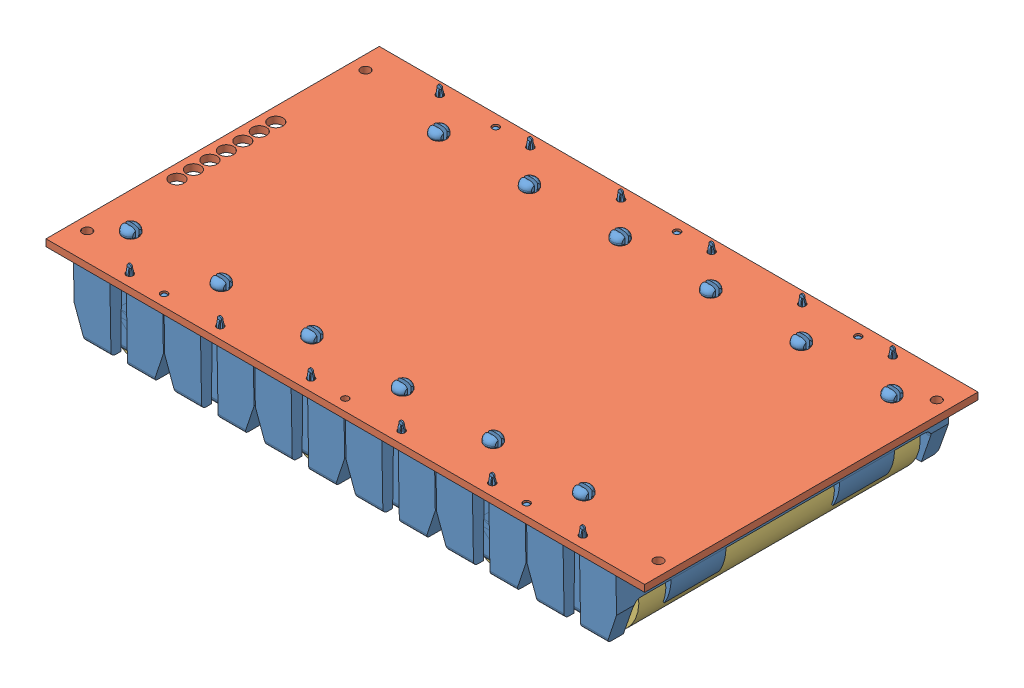
SolidWorks assembly PCB_Battery Assembly, configuration Default. Lengths in mm.
Overall size (138.43 24.87 77.22).
13 component instances, 3 part files, 30 mates.
Components (placement in the parent):
- Battery Holder - keystone-PN1043-1: Battery Holder - keystone-PN1043 [Default] at (-125.3925 103.3982 18.9155) x (1 0 0) z (0 0 -1) size (20.65 18.93 77.14)
- Battery PCB-1: Battery PCB [Default] at (-148.3186 115.135 -16.9005) x (1 0 0) z (0 -1 0) size (138.43 77.06 1.59)
- battery_6612-1: battery_6612 [Default] at (-117.0385 104.4035 -11.3639) x (-0.413992 0.91028 0) z (0.91028 0.413992 0) size (18.3 65.05 18.3)
- battery_6612-2: battery_6612 [Default] at (-137.9935 104.4035 54.6265) x (-0.916106 0.400937 0) z (-0.400937 -0.916106 0) size (18.3 65.05 18.3)
- Battery Holder - keystone-PN1043-2: Battery Holder - keystone-PN1043 [Default] at (-129.6396 103.3982 24.3471) x (-1 0 0) z (0 0 1) size (20.65 18.93 77.14)
- Battery Holder - keystone-PN1043-3: Battery Holder - keystone-PN1043 [Default] at (-104.4375 103.3982 18.9155) x (1 0 0) z (0 0 -1) size (20.65 18.93 77.14)
- battery_6612-3: battery_6612 [Default] at (-96.0835 104.4035 -10.3735) x (1 0 0) z (0 -1 0) size (18.3 65.05 18.3)
- Battery Holder - keystone-PN1043-4: Battery Holder - keystone-PN1043 [Default] at (-83.4825 103.3982 18.9155) x (1 0 0) z (0 0 -1) size (20.65 18.93 77.14)
- Battery Holder - keystone-PN1043-5: Battery Holder - keystone-PN1043 [Default] at (-45.8196 103.3982 24.3471) x (-1 0 0) z (0 0 1) size (20.65 18.93 77.14)
- Battery Holder - keystone-PN1043-6: Battery Holder - keystone-PN1043 [Default] at (-41.5725 103.3982 18.9155) x (1 0 0) z (0 0 -1) size (20.65 18.93 77.14)
- battery_6612-4: battery_6612 [Default] at (-75.1285 104.4035 -11.3639) x (-0.923728 -0.383049 0) z (-0.383049 0.923728 0) size (18.3 65.05 18.3)
- battery_6612-5: battery_6612 [Default] at (-54.1735 104.4035 54.6265) x (-1 0 0) z (0 -1 0) size (18.3 65.05 18.3)
- battery_6612-6: battery_6612 [Default] at (-33.2185 104.4035 -11.3639) x (-0.923728 -0.383049 0) z (-0.383049 0.923728 0) size (18.3 65.05 18.3)
Mates (geometry in assembly coordinates):
- Concentric1: concentric anti-aligned: cylinder of Battery Holder - keystone-PN1043-1 through (-117.0385 104.4035 -12.8111) axis (0 0 1) radius 9.144; cylinder of battery_6612-1 through (-117.0385 104.4035 53.6861) axis (0 0 -1) radius 9.15
- Coincident2: coincident anti-aligned: plane of Battery Holder - keystone-PN1043-1 through (-113.8635 103.7431 53.6861) normal (0 0 -1); plane of battery_6612-1 through (-117.0385 104.4035 53.6861) normal (0 0 1)
- Concentric4: concentric anti-aligned: cylinder of Battery Holder - keystone-PN1043-3 through (-96.0835 104.4035 -12.8111) axis (0 0 1) radius 9.144; cylinder of battery_6612-3 through (-96.0835 104.4035 54.6765) axis (0 0 -1) radius 9.15
- Coincident4: coincident anti-aligned: plane of Battery Holder - keystone-PN1043-3 through (-99.2585 103.7431 -10.3735) normal (0 0 1); plane of battery_6612-3 through (-96.0835 104.4035 -10.3735) normal (0 0 -1)
- Concentric5: concentric anti-aligned: cylinder of battery_6612-2 through (-137.9935 104.4035 -10.4235) axis (0 0 1) radius 9.15; cylinder of Battery Holder - keystone-PN1043-2 through (-137.9935 104.4035 56.0737) axis (0 0 -1) radius 9.144
- Coincident5: coincident anti-aligned: plane of battery_6612-2 through (-137.9935 104.4035 -10.4235) normal (0 0 -1); plane of Battery Holder - keystone-PN1043-2 through (-141.1685 103.7431 -10.4235) normal (0 0 1)
- Concentric12: concentric anti-aligned: cylinder of Battery PCB-1 through (-145.9945 113.5475 49.2538) axis (0 1 0) radius 1.7145; cylinder of Battery Holder - keystone-PN1043-2 through (-145.9945 113.5475 49.2538) axis (0 -1 0) radius 1.4605
- Coincident9: coincident aligned: plane of Battery PCB-1 through (-148.3186 113.5475 -16.9005) normal (0 -1 0); plane of Battery Holder - keystone-PN1043-2 through (-127.6684 113.5475 56.0737) normal (0 -1 0)
- Concentric13: concentric anti-aligned: cylinder of Battery PCB-1 through (-129.9925 113.5475 -5.9912) axis (0 1 0) radius 1.7145; cylinder of Battery Holder - keystone-PN1043-2 through (-129.9925 113.5475 -5.9912) axis (0 -1 0) radius 1.4605
- Coincident10: coincident aligned: plane of Battery Holder - keystone-PN1043-1 through (-127.3636 113.5475 -12.8111) normal (0 -1 0); plane of Battery PCB-1 through (-148.3186 113.5475 -16.9005) normal (0 -1 0)
- Concentric14: concentric anti-aligned: cylinder of Battery Holder - keystone-PN1043-1 through (-125.0395 113.5475 49.2538) axis (0 -1 0) radius 1.4605; cylinder of Battery PCB-1 through (-125.0395 113.5475 49.2538) axis (0 1 0) radius 1.7145
- Concentric15: concentric anti-aligned: cylinder of Battery Holder - keystone-PN1043-1 through (-109.0375 113.5475 -5.9912) axis (0 -1 0) radius 1.4605; cylinder of Battery PCB-1 through (-109.0375 113.5475 -5.9912) axis (0 1 0) radius 1.7145
- Coincident11: coincident aligned: plane of Battery PCB-1 through (-148.3186 113.5475 -16.9005) normal (0 -1 0); plane of Battery Holder - keystone-PN1043-3 through (-106.4086 113.5475 -12.8111) normal (0 -1 0)
- Concentric16: concentric anti-aligned: cylinder of Battery PCB-1 through (-104.0845 113.5475 49.2538) axis (0 1 0) radius 1.7145; cylinder of Battery Holder - keystone-PN1043-3 through (-104.0845 113.5475 49.2538) axis (0 -1 0) radius 1.4605
- Concentric17: concentric anti-aligned: cylinder of Battery PCB-1 through (-88.0825 113.5475 -5.9912) axis (0 1 0) radius 1.7145; cylinder of Battery Holder - keystone-PN1043-3 through (-88.0825 113.5475 -5.9912) axis (0 -1 0) radius 1.4605
- Concentric18: concentric anti-aligned: cylinder of Battery Holder - keystone-PN1043-6 through (-33.2185 104.4035 -12.8111) axis (0 0 1) radius 9.144; cylinder of battery_6612-6 through (-33.2185 104.4035 53.6861) axis (0 0 -1) radius 9.15
- Coincident12: coincident anti-aligned: plane of Battery Holder - keystone-PN1043-6 through (-30.0435 103.7431 53.6861) normal (0 0 -1); plane of battery_6612-6 through (-33.2185 104.4035 53.6861) normal (0 0 1)
- Concentric19: concentric anti-aligned: cylinder of Battery Holder - keystone-PN1043-5 through (-54.1735 104.4035 56.0737) axis (0 0 -1) radius 9.144; cylinder of battery_6612-5 through (-54.1735 104.4035 -10.4235) axis (0 0 1) radius 9.15
- Coincident13: coincident anti-aligned: plane of Battery Holder - keystone-PN1043-5 through (-57.3485 103.7431 -10.4235) normal (0 0 1); plane of battery_6612-5 through (-54.1735 104.4035 -10.4235) normal (0 0 -1)
- Concentric20: concentric anti-aligned: cylinder of Battery Holder - keystone-PN1043-4 through (-75.1285 104.4035 -12.8111) axis (0 0 1) radius 9.144; cylinder of battery_6612-4 through (-75.1285 104.4035 53.6861) axis (0 0 -1) radius 9.15
- Coincident14: coincident anti-aligned: plane of Battery Holder - keystone-PN1043-4 through (-71.9535 103.7431 53.6861) normal (0 0 -1); plane of battery_6612-4 through (-75.1285 104.4035 53.6861) normal (0 0 1)
- Coincident15: coincident aligned: plane of Battery PCB-1 through (-148.3186 113.5475 -16.9005) normal (0 -1 0); plane of Battery Holder - keystone-PN1043-4 through (-85.4536 113.5475 -12.8111) normal (0 -1 0)
- Concentric21: concentric anti-aligned: cylinder of Battery PCB-1 through (-83.1295 113.5475 49.2538) axis (0 1 0) radius 1.7145; cylinder of Battery Holder - keystone-PN1043-4 through (-83.1295 113.5475 49.2538) axis (0 -1 0) radius 1.4605
- Concentric22: concentric anti-aligned: cylinder of Battery PCB-1 through (-67.1275 113.5475 -5.9912) axis (0 1 0) radius 1.7145; cylinder of Battery Holder - keystone-PN1043-4 through (-67.1275 113.5475 -5.9912) axis (0 -1 0) radius 1.4605
- Coincident16: coincident aligned: plane of Battery PCB-1 through (-148.3186 113.5475 -16.9005) normal (0 -1 0); plane of Battery Holder - keystone-PN1043-5 through (-43.8484 113.5475 56.0737) normal (0 -1 0)
- Concentric23: concentric anti-aligned: cylinder of Battery Holder - keystone-PN1043-5 through (-62.1745 113.5475 49.2538) axis (0 -1 0) radius 1.4605; cylinder of Battery PCB-1 through (-62.1745 113.5475 49.2538) axis (0 1 0) radius 1.7145
- Concentric24: concentric anti-aligned: cylinder of Battery PCB-1 through (-46.1725 113.5475 -5.9912) axis (0 1 0) radius 1.7145; cylinder of Battery Holder - keystone-PN1043-5 through (-46.1725 113.5475 -5.9912) axis (0 -1 0) radius 1.4605
- Coincident17: coincident aligned: plane of Battery PCB-1 through (-148.3186 113.5475 -16.9005) normal (0 -1 0); plane of Battery Holder - keystone-PN1043-6 through (-43.5436 113.5475 -12.8111) normal (0 -1 0)
- Concentric26: concentric anti-aligned: cylinder of Battery PCB-1 through (-41.2195 113.5475 49.2538) axis (0 1 0) radius 1.7145; cylinder of Battery Holder - keystone-PN1043-6 through (-41.2195 113.5475 49.2538) axis (0 -1 0) radius 1.4605
- Concentric27: concentric anti-aligned: cylinder of Battery PCB-1 through (-25.2175 113.5475 -5.9912) axis (0 1 0) radius 1.7145; cylinder of Battery Holder - keystone-PN1043-6 through (-25.2175 113.5475 -5.9912) axis (0 -1 0) radius 1.4605
